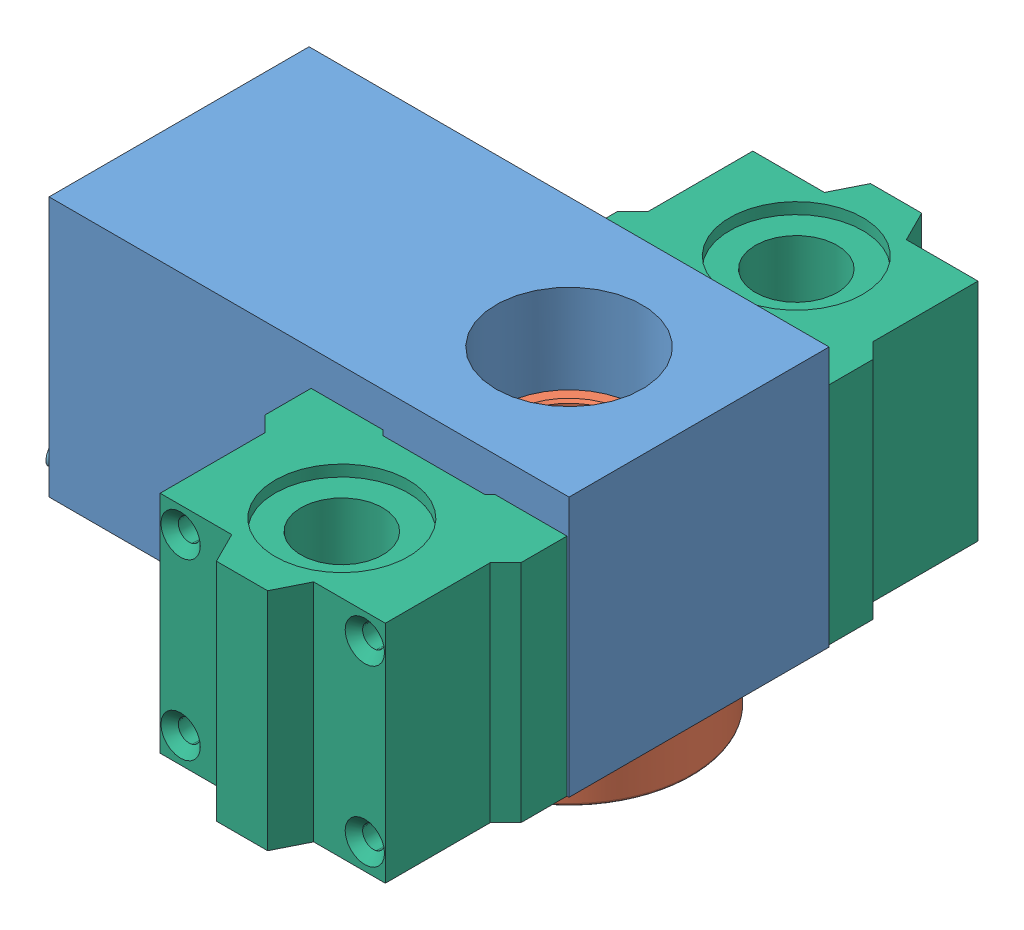
SolidWorks assembly Ball Screw Assembly, configuration Default. Lengths in mm.
Overall size (120.91 74.06 127.8).
8 component instances, 6 part files, 10 mates.
Components (placement in the parent):
- Ball Screw Connection-1: Ball Screw Connection [Default] at (63.7265 37.4659 0) size (101.6 50.8 50.8)
- SFU1605-1610-1-1: SFU1605-1610-1 [Default] at (89.1265 27.4659 0) x (-1 0 0) z (0 0 1) size (48 44 40)
- 0.5 INCH ROD END-1: 0.5 INCH ROD END [Default] at (109.6633 81.6101 -2.8109) x (0 0 -1) z (-1 0 0) size (18.44 41.52 30.53) (flexible)
  - 1_2-Heim_60645K181-3: 1_2-Heim_60645K181 [60645K181] at (-2.8109 40.4768 90.3868) size (17.46 41.27 6.35)
  - 1_2-Ball-60645K181-1: 1_2-Ball-60645K181 [60645K181] at (-2.8108 58.4317 90.3868) x (0.70138 -0.711605 0.041056) z (-0.209596 -0.150846 0.966082) size (12.15 12.15 6.35)
  - rod part-1: rod part [Default] at (-2.1454 58.9107 87.3195) x (-0.369316 -0.902628 -0.221063) z (-0.905359 0.403124 -0.133477) size (6.35 28.57 6.35)
- SCS16UU-1: SCS16UU [Valor predeterminado] at (89.1265 37.4659 -44.4) x (1 0 0) z (0 1 0) size (50 38.5 44)
- SCS16UU-3: SCS16UU [Valor predeterminado] at (89.1265 81.4659 44.4) x (1 0 0) z (0 -1 0) size (50 38.5 44)
Mates (geometry in assembly coordinates):
- Coincident1: coincident anti-aligned: plane of Ball Screw Connection-1 through (63.7265 37.4659 0) normal (0 -1 0); plane of SFU1605-1610-1-1 through (89.1265 37.4659 24) normal (0 1 0)
- Concentric1: concentric anti-aligned: cylinder of Ball Screw Connection-1 through (89.1265 37.4649 0) axis (0 1 0) radius 14.2875; cylinder of SFU1605-1610-1-1 through (89.1265 27.4659 0) axis (0 -1 0) radius 14
- Parallel1: parallel aligned: plane of Ball Screw Connection-1 through (12.9265 88.2659 -25.4) normal (0 0 -1); plane of SFU1605-1610-1-1 through (102.393 71.4669 -20) normal (0 0 -1)
- Concentric2: concentric aligned: cylinder of Ball Screw Connection-1 through (19.2765 37.4659 0) axis (0 -1 0) radius 2.7051; cylinder of 0.5 INCH ROD END-1/1_2-Heim_60645K181-3 through (19.2765 14.4471 0) axis (0 -1 0) radius 3.175
- Coincident3: coincident aligned: plane of Ball Screw Connection-1 through (63.7265 37.4659 0) normal (0 -1 0); circle of 0.5 INCH ROD END-1/1_2-Heim_60645K181-3
- Parallel2: parallel aligned: plane of Ball Screw Connection-1 through (12.9265 88.2659 25.4) normal (-1 0 0); plane of 0.5 INCH ROD END-1/1_2-Heim_60645K181-3 through (16.1015 14.4471 8.7312) normal (-1 0 0)
- Coincident4: coincident anti-aligned: plane of Ball Screw Connection-1 through (12.9265 88.2659 -25.4) normal (0 0 -1); plane of SCS16UU-1 through (64.1265 81.4659 -25.4) normal (0 0 1)
- Coincident5: coincident aligned: plane of Ball Screw Connection-1 through (63.7265 37.4659 0) normal (0 -1 0); plane of SCS16UU-1 through (67.1265 37.4659 -57.9) normal (0 -1 0)
- Coincident7: coincident: moEndPointRef_w of SCS16UU-1; plane of assembly
- Coincident11: coincident: moEndPointRef_w of Ball Screw Connection-1; plane of assembly
